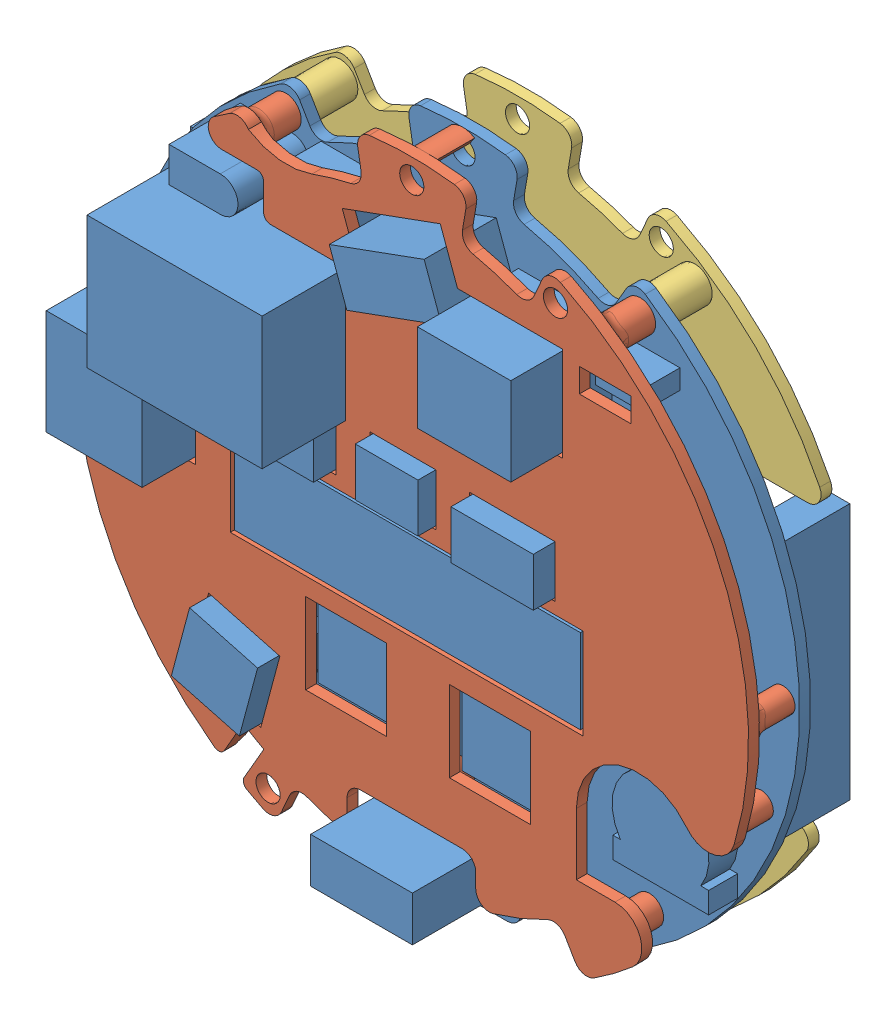
SolidWorks assembly bluebuzz_w_case_assembly, configuration Default. Lengths in mm.
Overall size (100 99.14 33.6).
3 component instances, 3 part files, 8 mates.
Components (placement in the parent):
- bluebuzz_pcb-1: bluebuzz_pcb [Default] at (-89.402 49.4818 9.1744) size (100 98.8 33.6)
- bluebuzz_case_transformer_side-1: bluebuzz_case_transformer_side [Default] at (-89.402 48.2704 16.7744) size (99.39 95.08 12.2)
- bluebuzz_case_compute_side-1: bluebuzz_case_compute_side [Default] at (-89.402 48.2704 2.6744) x (-1 0 0) z (0 0 -1) size (93.8 99.14 8.1)
Mates (geometry in assembly coordinates):
- Parallel1: parallel aligned: plane of bluebuzz_case_transformer_side-1 through (-89.402 48.2704 16.7744) normal (0 1 0)
- Parallel2: parallel aligned: plane of bluebuzz_case_transformer_side-1 through (-89.402 48.2704 16.7744) normal (1 0 0)
- Concentric1: concentric aligned: cylinder of bluebuzz_pcb-1 through (-89.402 48.2704 10.7744) axis (0 0 -1) radius 50; cylinder of bluebuzz_case_transformer_side-1 through (-89.402 48.2704 18.3744) axis (0 0 -1) radius 50
- Parallel3: parallel aligned: plane of bluebuzz_case_compute_side-1 through (-89.402 48.2704 2.6744) normal (0 1 0)
- Parallel4: parallel anti-aligned: plane of bluebuzz_case_compute_side-1 through (-89.402 48.2704 2.6744) normal (-1 0 0)
- Concentric2: concentric anti-aligned: cylinder of bluebuzz_pcb-1 through (-89.402 48.2704 10.7744) axis (0 0 -1) radius 50; cylinder of bluebuzz_case_compute_side-1 through (-89.402 48.2704 1.0744) axis (0 0 1) radius 50
- Distance1: distance = 6 mm anti-aligned: plane of bluebuzz_case_transformer_side-1 through (-89.402 48.2704 16.7744) normal (0 0 -1); plane of bluebuzz_pcb-1 through (-63.4297 7.904 10.7744) normal (0 0 1)
- Distance3: distance = 6.5 mm anti-aligned: plane of bluebuzz_case_compute_side-1 through (-89.402 48.2704 2.6744) normal (0 0 1); plane of bluebuzz_pcb-1 through (-63.4297 7.904 9.1744) normal (0 0 -1)
